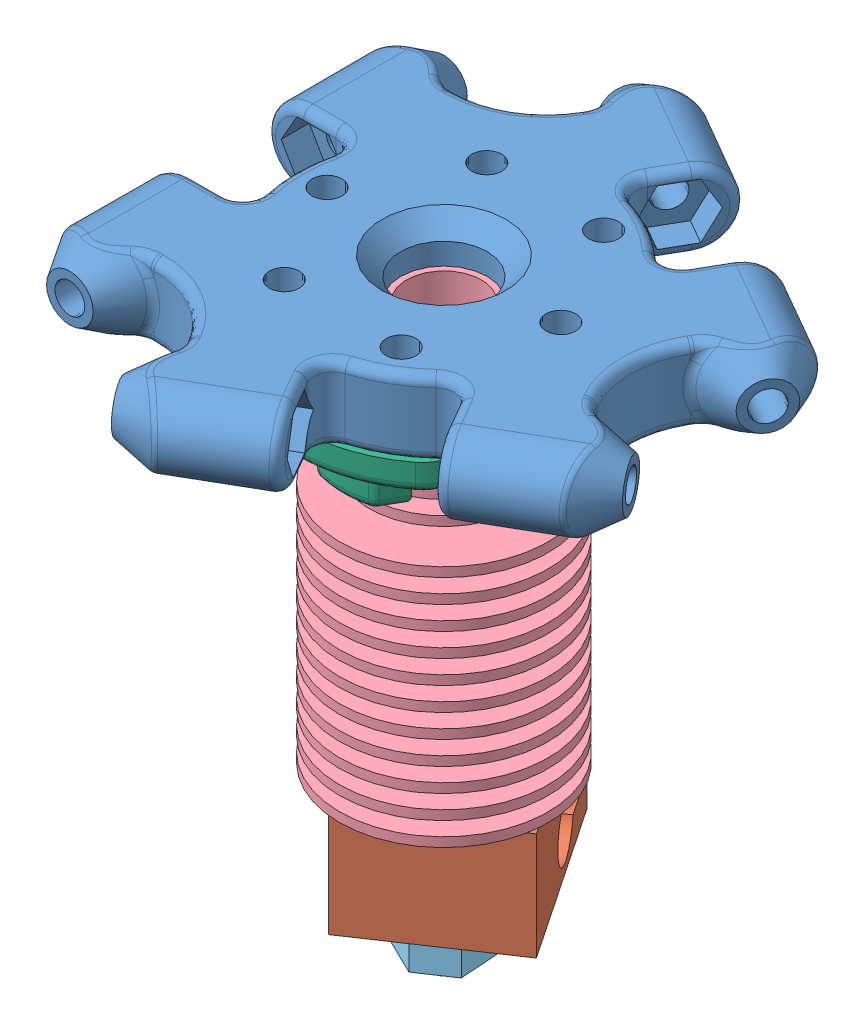
SolidWorks assembly assembled_hotend_e3dv6, configuration Default. Lengths in mm.
Overall size (61.18 66.45 68.41).
7 component instances, 6 part files, 6 mates.
Components (placement in the parent):
- effector-1: effector [Dual E3D Specific] at origin size (61.18 8.59 68.41)
- E3D V6 1.75 Uni model-2: E3D V6 1.75 Uni model [Default] at (8.2872 -64.2278 -16.0299) x (0.558296 0 0.829642) z (-0.829642 0 0.558296) size (26.95 61.85 22.9)
  - block^E3D V6 1.75 Uni model-1: block^E3D V6 1.75 Uni model [Default] at (3.1723 13.0752 15.8249) size (20 12.14 16) (virtual)
  - break^E3D V6 1.75 Uni model-1: break^E3D V6 1.75 Uni model [Default] at (8.6723 14.5752 15.8249) size (7.18 22.4 6.95) (virtual)
  - sink^E3D V6 1.75 Uni model-1: sink^E3D V6 1.75 Uni model [Default] at (8.6723 42.5778 15.8249) x (0.999633 0 0.027082) z (-0.027082 0 0.999633) size (22.3 42.99 22.3) (virtual)
  - nozzle^E3D V6 1.75 Uni model-1: nozzle^E3D V6 1.75 Uni model [Default] at (8.6723 2.0752 15.8249) size (7 12.82 8.08) (virtual)
- groovemount_clip_e3d-1: groovemount_clip_e3d [Default] at (0 -4 0) x (-1 0 0) z (0 -1 0) size (27.22 32 9.02)
Mates (geometry in assembly coordinates):
- Coincident2: coincident: plane of effector-1 through (-15 -0.3 25.9808) normal (0 -1 0); plane of E3D V6 1.75 Uni model-2/sink^E3D V6 1.75 Uni model-1 through (0 -0.3 0) normal (0 1 0)
- Concentric2: concentric: cylinder of effector-1 through (0 -4.2954 0) axis (0 -1 0) radius 4.2; cylinder of E3D V6 1.75 Uni model-2/sink^E3D V6 1.75 Uni model-1 through (0 -6.3 0) axis (0 1 0) radius 4
- InPlace2: in place: plane of effector-1 through (-15 -4 25.9808) normal (0 -1 0); plane of groovemount_clip_e3d-1 through (0 -4 0) normal (0 -1 0); moOrthogonalPlaneRef_w of effector-1 through (-15 -4 25.9808) normal (0 -1 0); unknown of groovemount_clip_e3d-1; plane of effector-1 through (-15 -4 25.9808) normal (0 -1 0); line of groovemount_clip_e3d-1 through (-55 0 -4) axis (0 -1 0); plane of effector-1 through (0 -4 0) normal (0 -1 0); unknown of groovemount_clip_e3d-1
- Coincident6: coincident aligned: plane of assembly through (0 0 0) normal (0 0 1)
- Coincident7: coincident aligned: moOrthogonalPlaneRef_w of effector-1 through (0 -4 0) normal (0 0 -1); plane of groovemount_clip_e3d-1
- Coincident8: coincident anti-aligned: moOrthogonalPlaneRef_w of effector-1 through (0 -4 0) normal (1 0 0); plane of groovemount_clip_e3d-1
